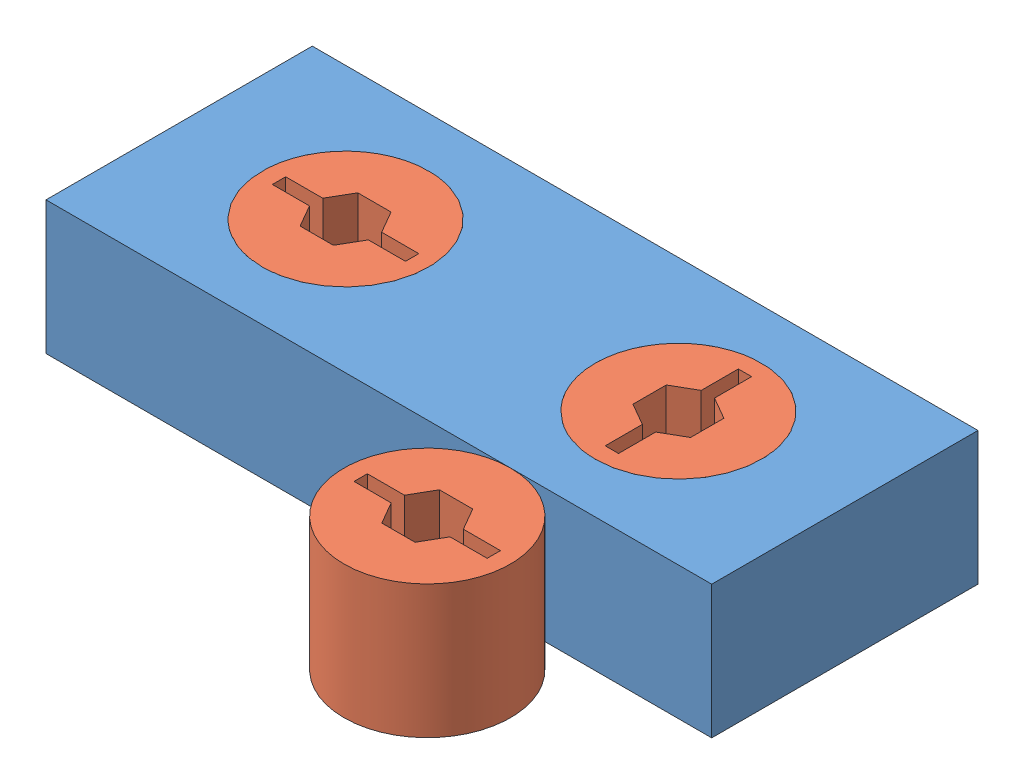
SolidWorks assembly Assem1, configuration Default. Lengths in mm.
Overall size (127 25.4 82.55).
4 component instances, 2 part files, 9 mates.
Components (placement in the parent):
- Block_circles_2013-1: Block_circles_2013 [Default] at (-13.4484 57.7362 118.6605) size (127 25.4 50.8)
- circles_2013-1: circles_2013 [Default] at (18.3016 57.7362 93.2605) size (31.75 25.4 31.75)
- circles_2013-2: circles_2013 [Default] at (75.1597 57.7362 134.5355) x (-1 0 0) z (0 0 -1) size (31.75 25.4 31.75)
- circles_2013-3: circles_2013 [Default] at (81.8016 57.7362 93.2605) x (0 0 -1) z (1 0 0) size (31.75 25.4 31.75)
Mates (geometry in assembly coordinates):
- Concentric1: concentric anti-aligned: cylinder of Block_circles_2013-1 through (18.3016 57.7362 93.2605) axis (0 1 0) radius 15.875; cylinder of circles_2013-1 through (18.3016 83.1362 93.2605) axis (0 -1 0) radius 15.875
- Coincident1: coincident aligned: plane of Block_circles_2013-1 through (-13.4484 83.1362 118.6605) normal (0 1 0); plane of circles_2013-1 through (18.3016 83.1362 93.2605) normal (0 1 0)
- Parallel1: parallel anti-aligned: line of Block_circles_2013-1 through (113.5516 83.1362 67.8605) axis (-1 0 0); line of circles_2013-1 through (5.6016 83.1362 91.9905) axis (1 0 0)
- Concentric2: concentric aligned: circle of Block_circles_2013-1; circle of circles_2013-3
- Coincident5: coincident aligned: plane of Block_circles_2013-1 through (-13.4484 83.1362 118.6605) normal (0 1 0); plane of circles_2013-3 through (81.8016 83.1362 93.2605) normal (0 1 0)
- Perpendicular2: perpendicular: plane of Block_circles_2013-1 through (-13.4484 83.1362 118.6605) normal (0 0 1); plane of circles_2013-3 through (87.3008 57.7362 93.2605) normal (-1 0 0)
- Tangent2: tangent anti-aligned: plane of Block_circles_2013-1 through (-13.4484 83.1362 118.6605) normal (0 0 1); cylinder of circles_2013-2 through (75.1597 83.1362 134.5355) axis (0 -1 0) radius 15.875
- Coincident7: coincident aligned: plane of Block_circles_2013-1 through (-13.4484 83.1362 118.6605) normal (0 1 0); plane of circles_2013-2 through (75.1597 83.1362 134.5355) normal (0 1 0)
- Parallel4: parallel aligned: plane of Block_circles_2013-1 through (-13.4484 83.1362 118.6605) normal (0 0 1); plane of circles_2013-2 through (75.1597 57.7362 129.0363) normal (0 0 1)
